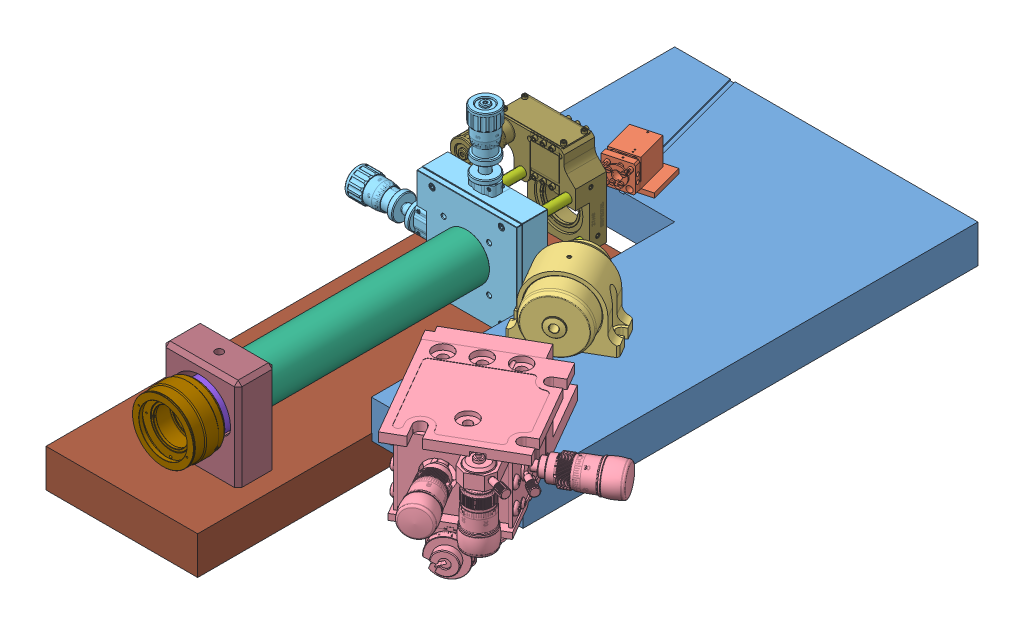
SolidWorks assembly optomechanical_assembly, configuration Default. Lengths in mm.
Overall size (335.52 142.67 437.7).
20 component instances, 14 part files, 0 mates.
Components (placement in the parent):
- fiber_launch_deflector-1: fiber_launch_deflector [Default] at (98.172 27.4759 -35.7557) x (0 0 -1) z (1 0 0) size (437.7 122.22 319.37)
  - deflector_holder_plate-1: deflector_holder_plate [Default] at origin size (300 25 200)
  - ASM003_fast_stage-1: ASM003_fast_stage [Default] at (-12.8928 39.6882 -38.0241) x (-0.965926 0 0.258819) z (-0.258819 0 -0.965926) size (32.45 22.3 32)
  - 110-21053-0003 REV A (DEFEATURED)-1: 110-21053-0003 REV A (DEFEATURED) [Default] at (-101.8016 47.225 31.0739) x (0.866025 0 -0.5) z (0.5 0 0.866025) size (55.94 44.23 55)
  - MBT621D_fiber_stage-1: MBT621D_fiber_stage [Default] at (-589.5078 116.225 347.4077) x (-0.866025 0 0.5) z (0.5 0 0.866025) size (157 87.61 116.56)
- telescope_assembly-1: telescope_assembly [Default] at (0.1654 13.5244 -24.5043) size (116.48 139.66 300)
  - ST1XY-D_pinhole_translation_stage-1: ST1XY-D_pinhole_translation_stage [Default] at (28.4444 18.502 77.2814) size (112.62 114.66 22.8)
  - SM1E60_lens_tube_long-1: SM1E60_lens_tube_long [Default] at (61.4644 51.522 164.0224) x (-0.096761 0.995308 0) z (0 0 -1) size (30.48 30.48 155.45)
  - ER2-P4_cage_rods-1: ER2-P4_cage_rods [Default] at (77.5245 65.4123 40.8865) x (0.999987 0.005042 0) z (0.005042 -0.999987 0) size (5.99 55.88 5.99)
  - ER2-P4_cage_rods-2: ER2-P4_cage_rods [Default] at (77.5245 35.4123 40.8865) x (0.999987 0.005042 0) z (0.005042 -0.999987 0) size (5.99 55.88 5.99)
  - ER2-P4_cage_rods-3: ER2-P4_cage_rods [Default] at (47.5245 65.4123 40.8865) x (0.999987 0.005042 0) z (0.005042 -0.999987 0) size (5.99 55.88 5.99)
  - ER2-P4_cage_rods-4: ER2-P4_cage_rods [Default] at (47.5245 35.4123 40.8865) x (0.999987 0.005042 0) z (0.005042 -0.999987 0) size (5.99 55.88 5.99)
  - SM1L10_lens_tue_extender-1: SM1L10_lens_tue_extender [Default] at (61.4644 51.522 267.9084) x (0 0 1) z (-0.974346 -0.225056 0) size (29.21 30.48 30.48)
  - SM1ZM_lens_z_adjuster-1: SM1ZM_lens_z_adjuster [Default] at (61.4644 51.522 277.6874) size (41.66 41.66 25.27)
  - P50S_50umpinhole-1: P50S_50umpinhole [Default] at (44.9788 60.0513 101.4906) x (0.923728 0.383049 0) z (0 0 -1) size (25.4 25.4 2.54)
  - telescope_holder-1: telescope_holder [Default] at (48.3417 -6.498 153.6286) x (0 0 -1) z (1 0 0) size (300 25 100)
  - SM1Z_cage_lens_z-2: SM1Z_cage_lens_z [Default] at (61.4529 51.5333 17.5964) x (-1 0 0) z (0 0 1) size (55.09 63.19 50.87)
  - lens_tube_holder-1: lens_tube_holder [Default] at (6.623 23.6113 266.6126) x (0 0 -1) z (1 0 0) size (25 60 50)
    - lens_tube_holder-1: lens_tube_holder [Default] at (1.5123 12.0928 54.7947) size (25 60 50)
    - 90291A535_CONFORMABLE SOFT NYLON-TIP SET SCREW-2: 90291A535_CONFORMABLE SOFT NYLON-TIP SET SCREW [90291A535] at (14.0123 44.173 54.8414) x (0.752673 0 -0.658395) z (0 1 0) size (6.52 6.42 11.64)
